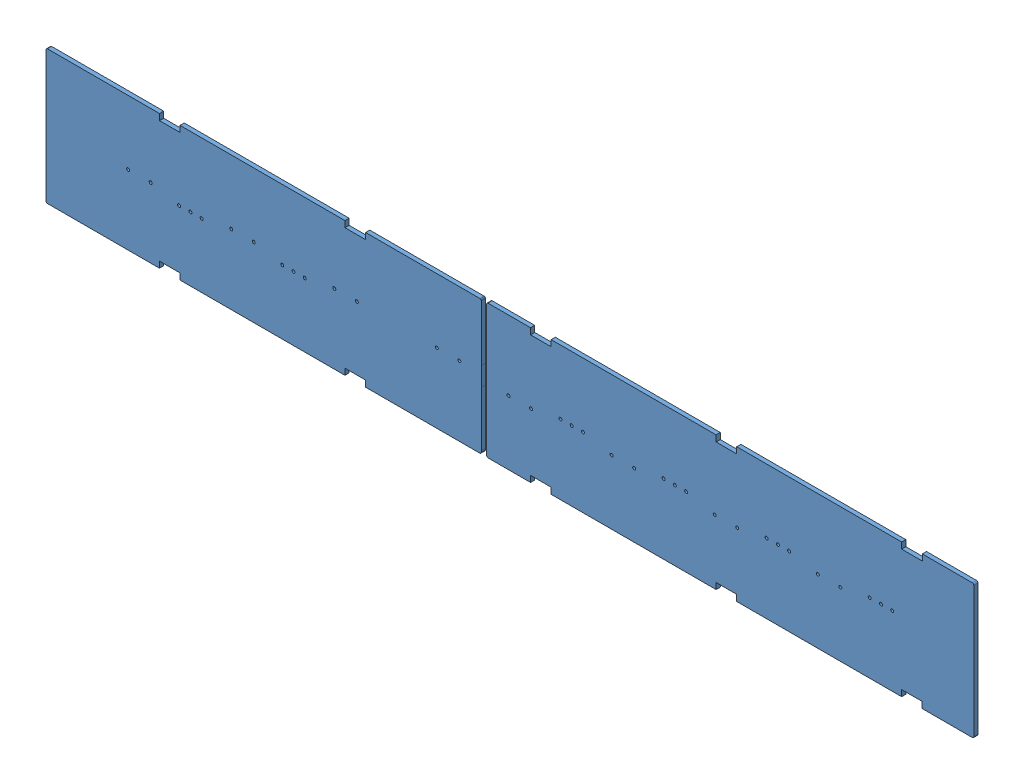
SolidWorks assembly 1PpGD.step, configuration По умолчанию. Lengths in mm.
Overall size (450 65 2.02).
3 component instances, 1 part files, 2 mates.
Components (placement in the parent):
- eBom-asm1.step-1: eBom-asm1.step [По умолчанию] at origin size (502.88 40.01 11.75) (suppressed, hidden)
- eBom-asm203.step-1: eBom-asm203.step [По умолчанию] at origin (suppressed, hidden)
- Power_plate.step-1: Power_plate.step [По умолчанию] at (0 -434.5628 0.8922) x (1 0 0) z (0 0 1) size (450 65 2.02)
Mates (geometry in assembly coordinates):
- Совпадение1: coincident aligned: plane of eBom-asm203.step-1/eBom-asm204.step-1/Board-45.step-1 through (0 -434.5628 -1.1281) normal (0 0 -1); plane of Power_plate.step-1 through (25.2 -396.1628 -1.1281) normal (0 0 -1)
- Совпадение4: coincident aligned: plane of eBom-asm203.step-1/eBom-asm204.step-1/Board-45.step-1 through (24.475 -331.9128 -1.1281) normal (-1 0 0); plane of Power_plate.step-1 through (24.475 -331.9128 -1.1281) normal (-1 0 0)
